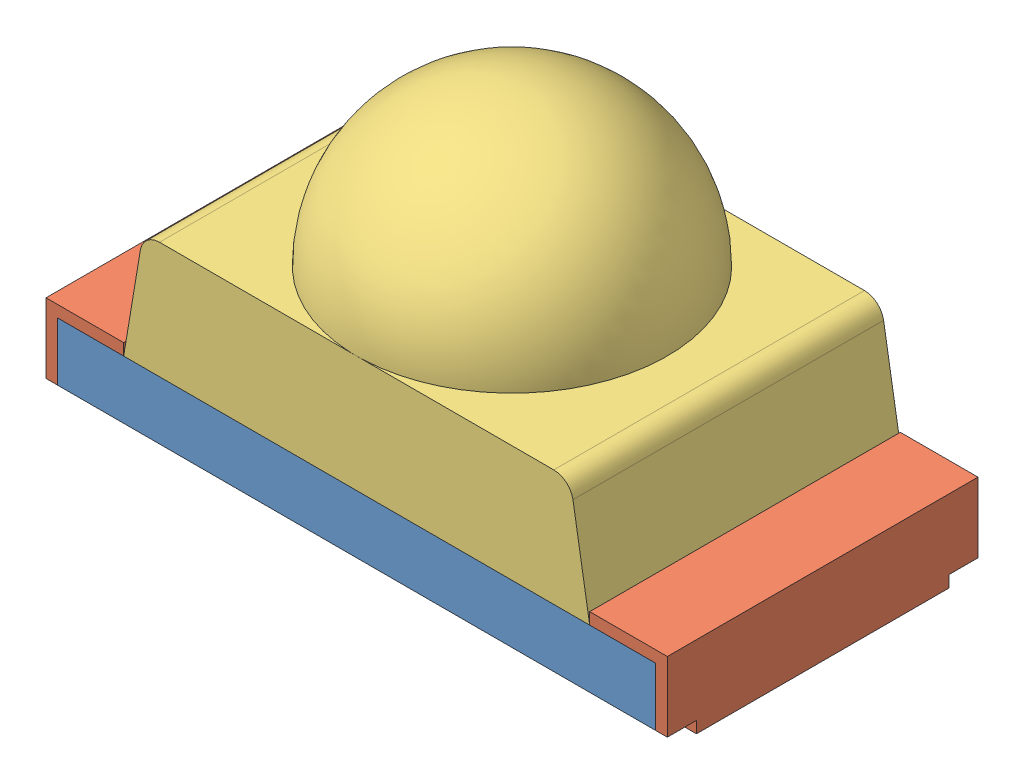
SolidWorks assembly LED0603R, configuration Default. Lengths in mm.
Overall size (1.6 0.88 0.8).
4 component instances, 3 part files, 9 mates.
Components (placement in the parent):
- LED0603-substrate-1: LED0603-substrate [Default] at (0 0.03 0) size (1.54 0.15 0.8)
- LED0603-clip-1: LED0603-clip [Default] at (-0.8 0.105 0) x (1 0 0) z (0 1 0) size (0.3 0.8 0.21)
- LED0603-clip-2: LED0603-clip [Default] at (0.8 0.105 0) x (-1 0 0) z (0 1 0) size (0.3 0.8 0.21)
- LED0603-lens-1: LED0603-lens [Default] at (0 0.18 0) size (1.2 0.7 0.8)
Mates (geometry in assembly coordinates):
- Coincident1: coincident aligned: plane of LED0603-substrate-1 through (0 0.03 0) normal (1 0 0)
- Coincident2: coincident aligned: plane of LED0603-substrate-1 through (0 0.03 0) normal (0 0 1)
- Distance1: distance = 0.03 mm aligned: plane of LED0603-substrate-1 through (0 0.03 0) normal (0 1 0)
- Coincident4: coincident anti-aligned: plane of LED0603-clip-1 through (-0.8 0.105 0) normal (0 0 -1)
- Coincident5: coincident anti-aligned: plane of LED0603-substrate-1 through (0 0.03 0) normal (0 -1 0); plane of LED0603-clip-1 through (-0.5 0.03 -0.4) normal (0 1 0)
- Coincident6: coincident anti-aligned: plane of LED0603-substrate-1 through (-0.77 0.18 0.4) normal (-1 0 0); plane of LED0603-clip-1 through (-0.77 0.18 -0.4) normal (1 0 0)
- Coincident7: coincident aligned: plane of LED0603-lens-1 through (0 0.18 0) normal (0 0 1)
- Coincident8: coincident aligned: plane of LED0603-lens-1 through (0 0.18 0) normal (1 0 0)
- Coincident9: coincident anti-aligned: plane of LED0603-substrate-1 through (0 0.18 0) normal (0 1 0); plane of LED0603-lens-1 through (0 0.18 0) normal (0 -1 0)
